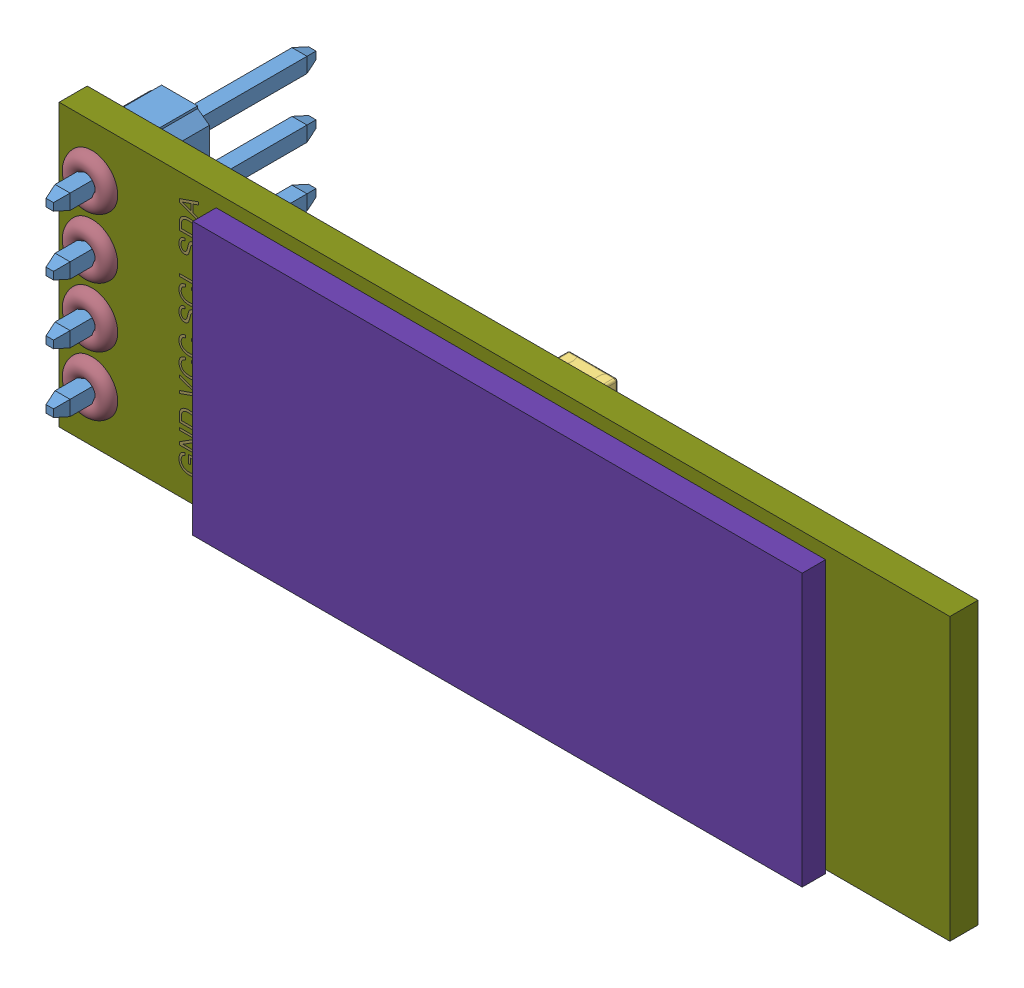
SolidWorks assembly OLED 128x32 Display, configuration Default. Lengths in mm.
Overall size (38 12 11.2).
18 component instances, 18 part files, 0 mates.
Components (placement in the parent):
- Copy of Fusion^OLED 128x32 Display-1: Copy of Fusion^OLED 128x32 Display [Default] at (1.4 6 0) x (0 1 0) z (0 0 -1) size (10.16 2.54 11.2) (virtual)
- Copy of SOLID005^OLED 128x32 Display-1: Copy of SOLID005^OLED 128x32 Display [Default] at (21 8.25 -0.6) size (2.1 1.35 0.7) (virtual)
- Copy of SOLID007^OLED 128x32 Display-1: Copy of SOLID007^OLED 128x32 Display [Default] at (21 11.25 -0.6) size (2.1 1.35 0.7) (virtual)
- Copy of SOLID006^OLED 128x32 Display-1: Copy of SOLID006^OLED 128x32 Display [Default] at (21 9.75 -0.6) size (2.1 1.35 0.7) (virtual)
- Copy of SOLID003^OLED 128x32 Display-1: Copy of SOLID003^OLED 128x32 Display [Default] at (21 5.25 -0.6) size (2.1 1.35 0.7) (virtual)
- Copy of SOLID004^OLED 128x32 Display-1: Copy of SOLID004^OLED 128x32 Display [Default] at (21 6.75 -0.6) size (2.1 1.35 0.7) (virtual)
- Copy of SOLID008^OLED 128x32 Display-1: Copy of SOLID008^OLED 128x32 Display [Default] at (13 3.75 -0.6) size (2.1 1.35 0.7) (virtual)
- Copy of SOLID009^OLED 128x32 Display-1: Copy of SOLID009^OLED 128x32 Display [Default] at (13 5.25 -0.6) size (2.1 1.35 0.7) (virtual)
- Copy of SOLID011^OLED 128x32 Display-1: Copy of SOLID011^OLED 128x32 Display [Default] at (13 8.25 -0.6) size (2.1 1.35 0.7) (virtual)
- Copy of SOLID012^OLED 128x32 Display-1: Copy of SOLID012^OLED 128x32 Display [Default] at (13 9.75 -0.6) size (2.1 1.35 0.7) (virtual)
- Copy of SOLID010^OLED 128x32 Display-1: Copy of SOLID010^OLED 128x32 Display [Default] at (13 6.75 -0.6) size (2.1 1.35 0.7) (virtual)
- Copy of ShapeString^OLED 128x32 Display-1: Copy of ShapeString^OLED 128x32 Display [Default] at (6 1 1.25) x (0 1 0) z (0 0 1) size (10.3 0.87 0.02) (virtual)
- Copy of Array^OLED 128x32 Display-1: Copy of Array^OLED 128x32 Display [Default] at origin size (2.2 9.82 0.8) (virtual)
- Copy of SOLID001^OLED 128x32 Display-1: Copy of SOLID001^OLED 128x32 Display [Default] at (21 2.25 -0.6) size (2.1 1.35 0.7) (virtual)
- Copy of SOLID002^OLED 128x32 Display-1: Copy of SOLID002^OLED 128x32 Display [Default] at (21 3.75 -0.6) size (2.1 1.35 0.7) (virtual)
- Copy of W_rfel^OLED 128x32 Display-1: Copy of W_rfel^OLED 128x32 Display [Default] at origin size (38 12 1.2) (virtual)
- Copy of W_rfel001^OLED 128x32 Display-1: Copy of W_rfel001^OLED 128x32 Display [Default] at (7 0.15 1.5) size (26 11.6 1) (virtual)
- Copy of PZ_TransistorSMD^OLED 128x32 Display-1: Copy of PZ_TransistorSMD^OLED 128x32 Display [Default] at (8 5 -0.5) x (1 0 0) z (0 1 0) size (2.5 1.11 3) (virtual)
